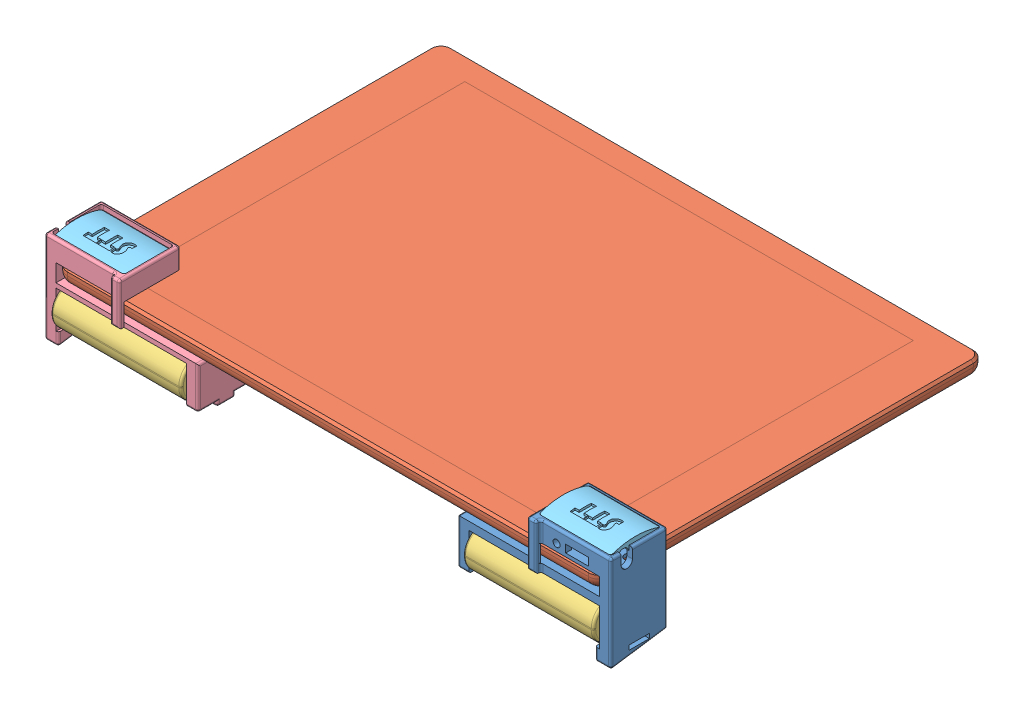
SolidWorks assembly W0000076-00-01 iPad MRT assy, configuration Default. Lengths in mm.
Overall size (250 44.18 172.5).
7 component instances, 5 part files, 18 mates.
Components (placement in the parent):
- W0000076-04-Ipad MRT-1: W0000076-04-Ipad MRT [Default] at (-65.2209 29.6623 6.2716) size (67.7 42.2 27)
- W0000076-05-iPad-1: W0000076-05-iPad [Default] at (-275.2209 22.1623 31.2716) size (240 7.5 170)
- W0000076-06-batterypack-1: W0000076-06-batterypack [Default] at (-92.9209 1.9623 33.7716) x (0 0 -1) z (1 0 0) size (30 16.5 57.5)
- W0000076-07-Ipad MRT Mirror-1: W0000076-07-Ipad MRT Mirror [Default] at (-245.2209 29.6623 31.2716) x (-1 0 0) z (0 0 -1) size (67.7 40.7 27)
- W0000076-06-batterypack-2: W0000076-06-batterypack [Default] at (-217.5209 3.4623 3.7716) x (0 0 1) z (-1 0 0) size (30 16.5 57.5)
- W0000076-08-iPadmrtcover-1: W0000076-08-iPadmrtcover [Default] at (-31.7209 38.6623 7.9716) x (-1 0 0) z (0 0 -1) size (31.8 3.98 21.8)
- W0000076-08-iPadmrtcover-2: W0000076-08-iPadmrtcover [Default] at (-246.7209 36.6623 7.9716) x (-1 0 0) z (0 0 -1) size (31.8 3.98 21.8)
Mates (geometry in assembly coordinates):
- Coincident1: coincident anti-aligned: plane of W0000076-04-Ipad MRT-1 through (-65.2209 29.6623 31.2716) normal (0 0 -1); plane of W0000076-05-iPad-1 through (-270.2209 29.6623 31.2716) normal (0 0 1)
- Coincident2: coincident anti-aligned: plane of W0000076-04-Ipad MRT-1 through (-35.2209 29.6623 31.2716) normal (-1 0 0); plane of W0000076-05-iPad-1 through (-35.2209 29.6623 26.2716) normal (1 0 0)
- Coincident3: coincident anti-aligned: plane of W0000076-04-Ipad MRT-1 through (-65.2209 29.6623 31.2716) normal (0 -1 0); plane of W0000076-05-iPad-1 through (-270.2209 29.6623 26.2716) normal (0 1 0)
- Coincident5: coincident anti-aligned: plane of W0000076-04-Ipad MRT-1 through (-92.9209 1.9623 6.2716) normal (1 0 0); plane of W0000076-06-batterypack-1 through (-92.9209 9.9623 25.7716) normal (-1 0 0)
- Coincident6: coincident anti-aligned: plane of W0000076-04-Ipad MRT-1 through (-35.2209 18.4623 6.2716) normal (0 -1 0); plane of W0000076-06-batterypack-1 through (-35.4209 18.4623 25.7716) normal (0 1 0)
- Distance1: distance = 2.5 mm aligned: plane of W0000076-06-batterypack-1 through (-35.4209 9.9623 33.7716) normal (0 0 1); plane of W0000076-04-Ipad MRT-1 through (-65.2209 29.6623 31.2716) normal (0 0 1)
- Coincident8: coincident anti-aligned: plane of W0000076-05-iPad-1 through (-275.2209 29.6623 26.2716) normal (-1 0 0); plane of W0000076-07-Ipad MRT Mirror-1 through (-275.2209 29.6623 6.2716) normal (1 0 0)
- Coincident9: coincident anti-aligned: plane of W0000076-05-iPad-1 through (-270.2209 29.6623 26.2716) normal (0 1 0); plane of W0000076-07-Ipad MRT Mirror-1 through (-245.2209 29.6623 6.2716) normal (0 -1 0)
- Coincident10: coincident anti-aligned: plane of W0000076-05-iPad-1 through (-270.2209 29.6623 31.2716) normal (0 0 1); plane of W0000076-07-Ipad MRT Mirror-1 through (-245.2209 29.6623 31.2716) normal (0 0 -1)
- Coincident11: coincident anti-aligned: plane of W0000076-07-Ipad MRT Mirror-1 through (-217.5209 3.4623 31.2716) normal (-1 0 0); plane of W0000076-06-batterypack-2 through (-217.5209 11.4623 11.7716) normal (1 0 0)
- Coincident12: coincident anti-aligned: plane of W0000076-07-Ipad MRT Mirror-1 through (-275.2209 19.9623 31.2716) normal (0 -1 0); plane of W0000076-06-batterypack-2 through (-275.0209 19.9623 11.7716) normal (0 1 0)
- Coincident13: coincident aligned: plane of W0000076-06-batterypack-1 through (-35.4209 9.9623 3.7716) normal (0 0 -1); plane of W0000076-06-batterypack-2 through (-275.0209 11.4623 3.7716) normal (0 0 -1)
- Coincident14: coincident anti-aligned: plane of W0000076-04-Ipad MRT-1 through (-31.7209 36.6623 29.7716) normal (0 0 -1); plane of W0000076-08-iPadmrtcover-1 through (-31.7209 40.6623 29.7716) normal (0 0 1)
- Coincident15: coincident anti-aligned: plane of W0000076-04-Ipad MRT-1 through (-31.7209 36.6623 29.7716) normal (-1 0 0); plane of W0000076-08-iPadmrtcover-1 through (-31.7209 40.6623 7.9716) normal (1 0 0)
- Coincident17: coincident anti-aligned: plane of W0000076-07-Ipad MRT Mirror-1 through (-278.7209 36.6623 29.7716) normal (0 0 -1); plane of W0000076-08-iPadmrtcover-2 through (-246.7209 38.6623 29.7716) normal (0 0 1)
- Coincident18: coincident anti-aligned: plane of W0000076-07-Ipad MRT Mirror-1 through (-246.7209 36.6623 7.7716) normal (-1 0 0); plane of W0000076-08-iPadmrtcover-2 through (-246.7209 38.6623 7.9716) normal (1 0 0)
- Coincident19: coincident anti-aligned: plane of W0000076-07-Ipad MRT Mirror-1 through (-245.2209 36.6623 31.2716) normal (0 1 0); plane of W0000076-08-iPadmrtcover-2 through (-246.7209 36.6623 7.9716) normal (0 -1 0)
- Coincident20: coincident anti-aligned: plane of W0000076-04-Ipad MRT-1 through (-65.2209 36.6623 6.2716) normal (0 1 0); plane of W0000076-08-iPadmrtcover-1 through (-32.7209 36.6623 8.9716) normal (0 -1 0)
